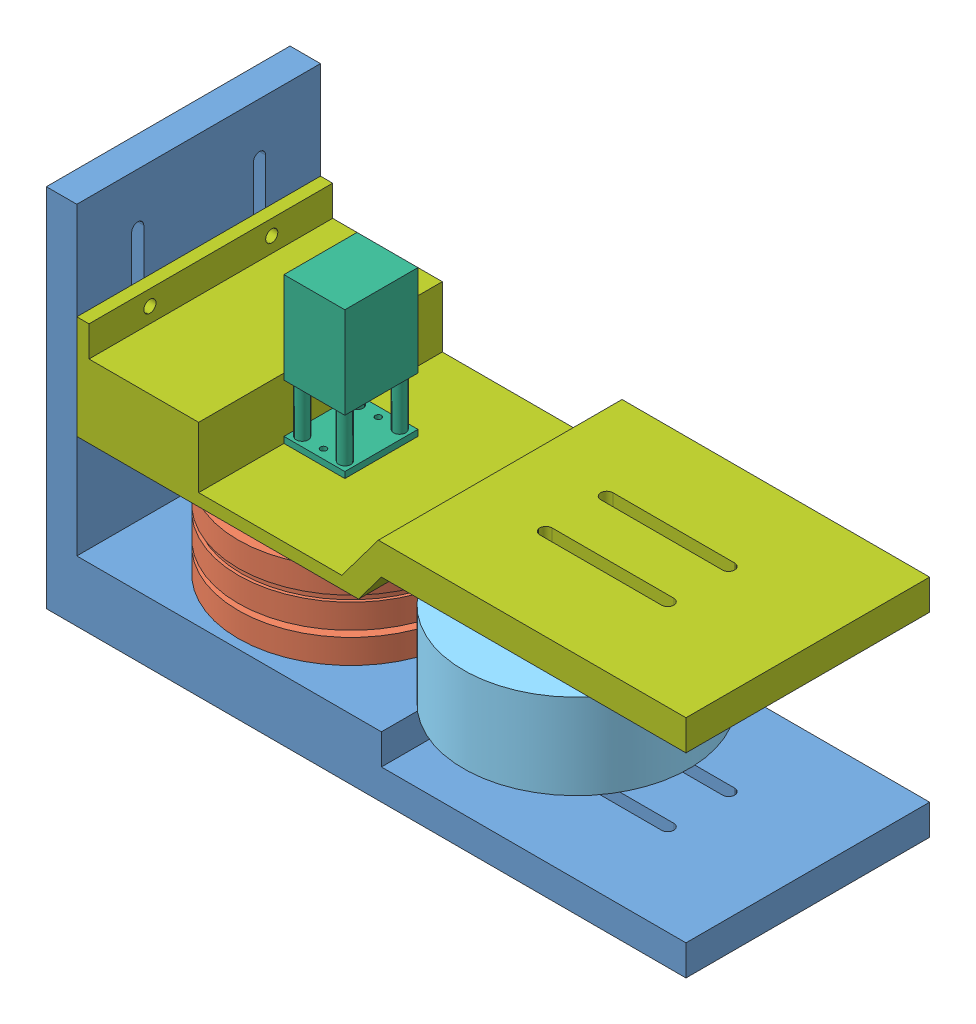
SolidWorks assembly 装配体, configuration 默认. Lengths in mm.
Overall size (105 60 51.08).
10 component instances, 8 part files, 25 mates.
Components (placement in the parent):
- 基座-1: 基座 [默认] at (-17.2183 0.195 40) x (0 -1 0) z (1 0 0) size (60 40 105)
- 送丝轮-1: 送丝轮 [默认] at (12.7817 -9.805 40) x (0 0 1) z (0 1 0) size (37 37 14)
- 轴承-1: 轴承 [默认] at (12.7817 -19.805 40) x (-1 0 0) z (0 1 0) size (6 6 2.5)
- 预紧轮滑动支架-1: 预紧轮滑动支架 [默认] at (49.7817 -24.805 40) x (0 0 1) z (0 1 0) size (20 10 7.5)
- 预紧轮-1: 预紧轮 [默认] at (49.7817 -19.805 40) x (-0.843747 0 -0.536741) z (0 1 0) size (37 37 14)
- 轴承-2: 轴承 [默认] at (49.7817 -19.805 40) x (-1 0 0) z (0 1 0) size (6 6 2.5)
- 电机-1: 电机 [默认] at (12.7817 0.195 40) x (0 0 -1) z (0 -1 0) size (12 10 35)
- 电机支架-1: 电机支架 [默认] at (7.7817 3.195 40) x (0 0 -1) z (-1 0 0) size (40 17 100)
- 预紧轮滑动支架—2-1: 预紧轮滑动支架—2 [默认] at (49.7817 2.195 40) x (0 0 1) z (0 -1 0) size (20 10 10.5)
- 轴承-3: 轴承 [默认] at (49.7817 -8.305 40) x (1 0 0) z (0 1 0) size (6 6 2.5)
Mates (geometry in assembly coordinates):
- 同心1: concentric aligned: cylinder of 送丝轮-1 through (12.7817 -17.305 40) axis (0 -1 0) radius 3; cylinder of 轴承-1 through (12.7817 -17.305 40) axis (0 -1 0) radius 3
- 重合1: coincident anti-aligned: plane of 送丝轮-1 through (12.7817 -17.305 40) normal (0 -1 0); plane of 轴承-1 through (12.7817 -17.305 40) normal (0 1 0)
- 同心2: concentric aligned: cylinder of 基座-1 through (12.7817 -17.305 40) axis (0 -1 0) radius 1; cylinder of 轴承-1 through (12.7817 -17.305 40) axis (0 -1 0) radius 1
- 同心3: concentric aligned: circle of 基座-1; circle of 轴承-1
- 重合5: coincident aligned: circle of 基座-1; circle of 轴承-1
- 相切1: tangent anti-aligned: plane of 基座-1 through (49.7817 -29.805 46) normal (0 0 -1); cylinder of 预紧轮滑动支架-1 through (49.7817 -19.805 45) axis (0 -1 0) radius 1
- 重合7: coincident anti-aligned: plane of 基座-1 through (87.7817 -24.805 20) normal (0 1 0); plane of 预紧轮滑动支架-1 through (49.7817 -24.805 40) normal (0 -1 0)
- 相切3: tangent anti-aligned: plane of 基座-1 through (49.7817 -29.805 34) normal (0 0 1); cylinder of 预紧轮滑动支架-1 through (49.7817 -19.805 35) axis (0 -1 0) radius 1
- 同心6: concentric aligned: cylinder of 预紧轮-1 through (49.7817 -17.305 40) axis (0 -1 0) radius 3; cylinder of 轴承-2 through (49.7817 -17.305 40) axis (0 -1 0) radius 3
- 重合8: coincident anti-aligned: plane of 预紧轮-1 through (49.7817 -17.305 40) normal (0 -1 0); plane of 轴承-2 through (49.7817 -17.305 40) normal (0 1 0)
- 同心7: concentric aligned: line of 预紧轮滑动支架-1 through (49.7817 -17.305 40) axis (0 -1 0); cylinder of 轴承-2 through (49.7817 -17.305 40) axis (0 -1 0) radius 1
- 重合9: coincident aligned: circle of 预紧轮滑动支架-1; circle of 轴承-2
- 同心8: concentric anti-aligned: cylinder of 基座-1 through (49.7817 -29.805 35) axis (0 1 0) radius 1; cylinder of 预紧轮滑动支架-1 through (49.7817 -19.805 35) axis (0 -1 0) radius 1
- 重合10: coincident anti-aligned: plane of 送丝轮-1 through (13.7817 -11.805 41.118) normal (-1 0 0); plane of 电机-1 through (13.7817 -11.805 41.118) normal (1 0 0)
- 同心9: concentric aligned: cylinder of 送丝轮-1 through (12.7817 -11.805 40) axis (0 1 0) radius 1.5; cylinder of 电机-1 through (12.7817 -11.805 40) axis (0 1 0) radius 1.5
- 重合11: coincident anti-aligned: plane of 送丝轮-1 through (12.7817 -11.805 40) normal (0 1 0); plane of 电机-1 through (12.7817 -11.805 40) normal (0 -1 0)
- 平行1: parallel aligned: plane of 基座-1 through (-12.2183 0.195 40) normal (1 0 0); plane of 电机-1 through (17.7817 23.195 34) normal (1 0 0)
- 重合13: coincident anti-aligned: plane of 基座-1 through (-12.2183 0.195 40) normal (1 0 0); plane of 电机支架-1 through (-12.2183 3.195 40) normal (-1 0 0)
- 重合14: coincident aligned: plane of 基座-1 through (-12.2183 30.195 20) normal (0 0 -1); plane of 电机支架-1 through (-12.2183 -2.805 20) normal (0 0 -1)
- 重合16: coincident anti-aligned: plane of 电机-1 through (12.7817 -0.805 40) normal (0 -1 0); plane of 电机支架-1 through (31.2817 -0.805 20) normal (0 1 0)
- 同心10: concentric anti-aligned: cylinder of 电机支架-1 through (49.7817 14.196 35) axis (0 -1 0) radius 1; cylinder of 预紧轮滑动支架—2-1 through (49.7817 -2.805 35) axis (0 1 0) radius 1
- 同心11: concentric anti-aligned: cylinder of 电机支架-1 through (49.7817 14.196 45) axis (0 -1 0) radius 1; cylinder of 预紧轮滑动支架—2-1 through (49.7817 -2.805 45) axis (0 1 0) radius 1
- 重合17: coincident anti-aligned: plane of 电机支架-1 through (87.7817 2.195 -33.9821) normal (0 -1 0); plane of 预紧轮滑动支架—2-1 through (49.7817 2.195 40) normal (0 1 0)
- 同心12: concentric anti-aligned: cylinder of 预紧轮-1 through (49.7817 -8.305 40) axis (0 1 0) radius 3; cylinder of 轴承-3 through (49.7817 -5.805 40) axis (0 -1 0) radius 3
- 重合18: coincident aligned: plane of 预紧轮-1 through (49.7817 -5.805 40) normal (0 1 0); plane of 轴承-3 through (49.7817 -5.805 40) normal (0 1 0)
